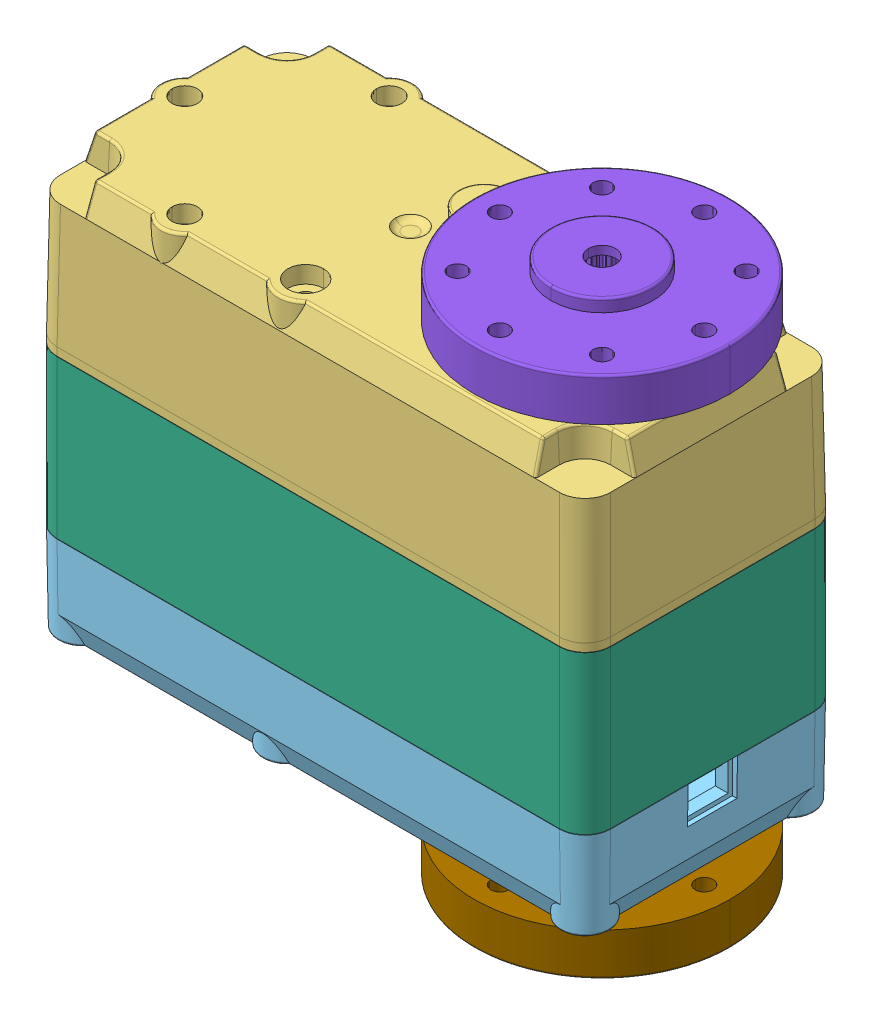
SolidWorks assembly asm-RDS5160, configuration 默认. Lengths in mm.
Overall size (67.05 63.2 30.1).
10 component instances, 9 part files, 0 mates.
Components (placement in the parent):
- asm-RDS5160.stp-1: asm-RDS5160.stp [默认] at origin size (67.05 63.2 30.1)
  - MOTOR-280.stp-1: MOTOR-280.stp [默认] at (-18.5 -25.5 0) x (0 0 -1) z (1 0 0) size (24 41 24)
  - GM.stp-1: GM.stp [默认] at (-18.5 10.7 0) x (-1 0 0) z (0 1 0) size (5.06 5.06 3)
  - SG.stp-1: SG.stp [默认] at origin size (65.1 20 30.1)
  - ZK.stp-1: ZK.stp [默认] at origin size (62.41 12.7 27.41)
  - DG.stp-1: DG.stp [默认] at origin size (65 17.45 30)
  - LVKE-6530.stp-1: LVKE-6530.stp [默认] at origin size (65 19.9 30)
  - BEISHIZHOUCHENG-6-13-5.stp-1: BEISHIZHOUCHENG-6-13-5.stp [默认] at (19.5 -33.2 0) x (-1 0 0) z (0 0 1) size (15 5 15)
  - DDP-1.stp-1: DDP-1.stp [默认] at (19.5 21.2 0) size (30 6.5 30)
  - DDP-CD.stp-1: DDP-CD.stp [默认] at (19.5 -33.2 0) x (-1 0 0) z (0 0 1) size (30 5 30)
